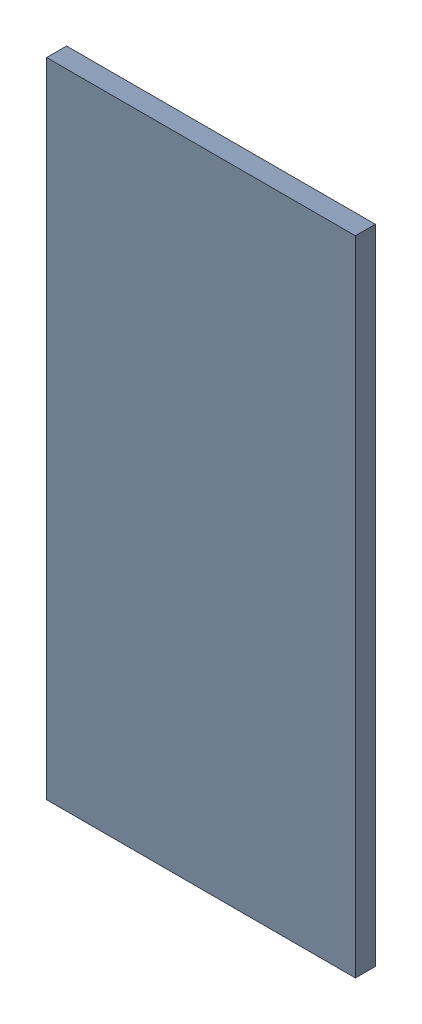
SolidWorks assembly Pad ADXL345-12(22.2mm,55.903mm) on Top Layer, configuration Predeterminado. Lengths in mm.
Overall size (0.55 1.15 0.04).
2 component instances, 1 part files, 0 mates.
Components (placement in the parent):
- Pad ADXL345-12(22.2mm,55.903mm) on Top Layer-1-1: Pad ADXL345-12(22.2mm,55.903mm) on Top Layer-1 [Predeterminado] at (-68.317 -44.187 -0.0457) size (0.55 1.15 0.04)
  - Pad ADXL345-12(22.2mm,55.903mm) on Top Layer-Part-1-1: Pad ADXL345-12(22.2mm,55.903mm) on Top Layer-Part-1 [Predeterminado] at origin size (0.55 1.15 0.04)
